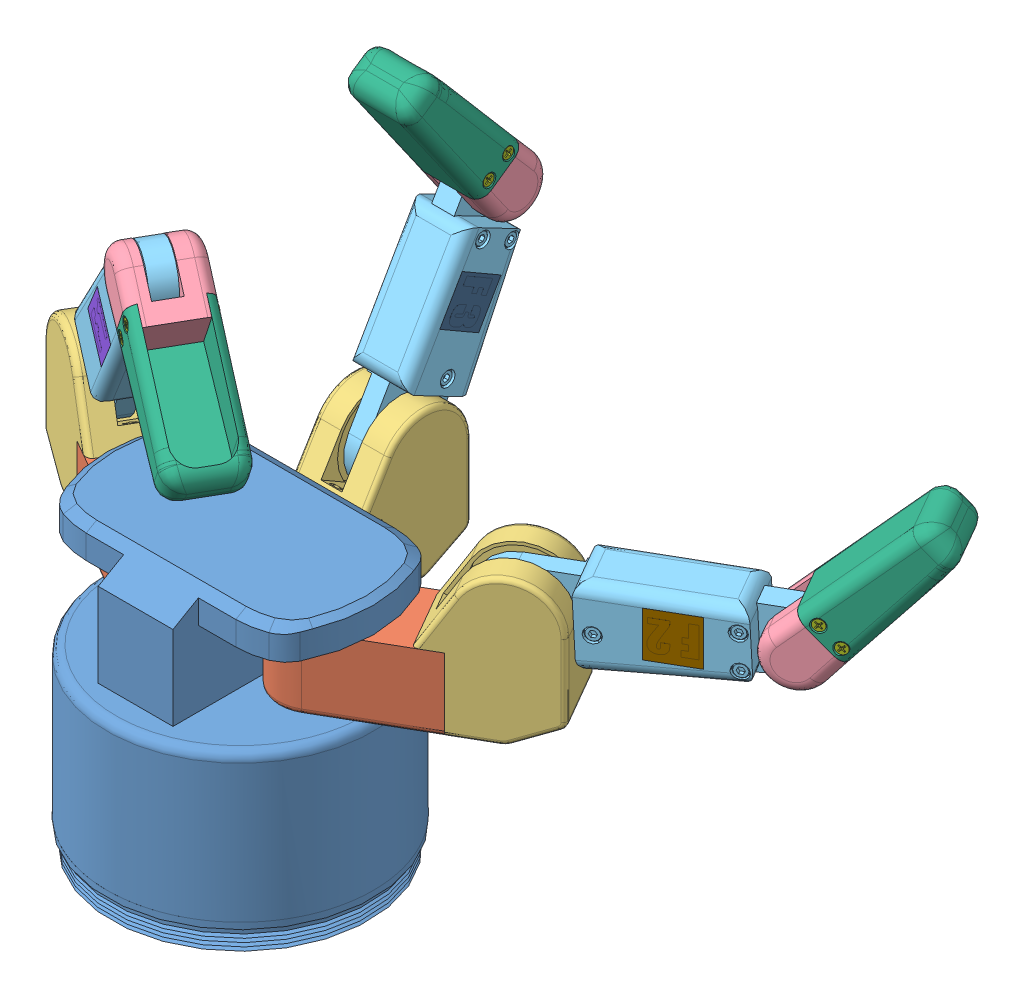
SolidWorks assembly B2579, configuration Default. Lengths in mm.
Overall size (264.08 206.15 142.32).
52 component instances, 10 part files, 12 mates.
Components (placement in the parent):
- B2580-1: B2580 [Default] at (0 -38 0) size (122.92 94.5 88.91)
  - B2581-1: B2581 [Default] at origin size (89 94.5 88.91)
  - B2582-1: B2582 [Default] at (-25 3.2 0) x (-0.5 0 0.866025) z (-0.866025 0 -0.5) size (24.6 24.6 47.3)
  - B2582-2: B2582 [Default] at (25 3.2 0) x (-0.5 0 -0.866025) z (0.866025 0 -0.5) size (24.6 24.6 47.3)
- B2587-1: B2587 [F1] at (-68.3013 -1.1 -25) x (0.5 0 -0.866025) z (0.866025 0 0.5) size (24.6 104.22 112.16)
  - B2583-1: B2583 [Default] at origin size (24.6 48.5 38)
  - B2584-1: B2584 [Default] at (0 55.5766 42.5587) x (1 0 0) z (0 -0.524977 0.851117) size (23 19 25.5)
  - B2585-1: B2585 [Default] x (1 0 0) z (0 0.793951 0.607982) size (19.77 26.65 92)
  - B2586-1: B2586 [Default] at (0.1 18.0923 85.234) x (1 0 0) z (0 -0.524977 0.851117) size (23.31 17.9 46)
    - B0926-1: B0926 [Default] at (0 0 -46) x (-1 0 0) z (0 1 0) size (23.31 46 17.9)
    - B1090-1: B1090 [M2-.4x6] at (10.3 13.5 -43) x (-1 0 0) z (0 0 1) size (6 3.6 3.6)
    - B1090-2: B1090 [M2-.4x6] at (10.3 5.5 -43) x (-1 0 0) z (0 -1 0) size (6 3.6 3.6)
    - B1090-3: B1090 [M2-.4x6] at (-10.3 5.5 -43) size (6 3.6 3.6)
    - B1090-4: B1090 [M2-.4x6] at (-10.3 13.5 -43) x (1 0 0) z (0 -1 0) size (6 3.6 3.6)
  - B0990-1: B0990 [Default] at (9.85 30.4111 25.5623) x (0 -0.819152 -0.573576) z (1 0 0) size (15 15 0.02)
  - B0990-2: B0990 [Default] at (-9.75 30.9368 25.9304) x (0 0.819152 0.573576) z (-1 0 0) size (15 15 0.02)
  - B0991-1: B0991 [Default] at (-9.75 3.4963 -40.215) x (0 0 -1) z (-1 0 0) (suppressed, hidden)
  - B0991-2: B0991 [Default] at (9.85 3.4963 -40.215) x (0 0 1) z (1 0 0) (suppressed, hidden)
  - B0992-1: B0992 [Default] at (-9.75 36.5754 -17.0796) x (0 0.866025 -0.5) z (-1 0 0) (suppressed, hidden)
  - B0992-2: B0992 [Default] at (9.85 36.5754 -17.0796) x (0 -0.866025 0.5) z (1 0 0) (suppressed, hidden)
- B2587-2: B2587 [F2] at (68.3013 -1.1 -25) x (0.5 0 0.866025) z (-0.866025 0 0.5) size (24.6 82.8 138.47)
  - B2583-1: B2583 [Default] at origin size (24.6 48.5 38)
  - B2584-1: B2584 [Default] at (0 2.9847 -69.9363) x (1 0 0) z (0 0.707107 -0.707107) size (23 19 25.5)
  - B2585-1: B2585 [Default] x (1 0 0) z (0 0.042638 -0.999091) size (19.77 26.65 92)
  - B2586-1: B2586 [Default] at (0.1 49.3001 -102.8168) x (1 0 0) z (0 0.707107 -0.707107) size (23.31 17.9 46)
    - B0926-1: B0926 [Default] at (0 0 -46) x (-1 0 0) z (0 1 0) size (23.31 46 17.9)
    - B1090-1: B1090 [M2-.4x6] at (10.3 13.5 -43) x (-1 0 0) z (0 0 1) size (6 3.6 3.6)
    - B1090-2: B1090 [M2-.4x6] at (10.3 5.5 -43) x (-1 0 0) z (0 -1 0) size (6 3.6 3.6)
    - B1090-3: B1090 [M2-.4x6] at (-10.3 5.5 -43) size (6 3.6 3.6)
    - B1090-4: B1090 [M2-.4x6] at (-10.3 13.5 -43) x (1 0 0) z (0 -1 0) size (6 3.6 3.6)
  - B0990-1: B0990 [Default] at (9.85 30.4111 25.5623) x (0 -0.819152 -0.573576) z (1 0 0) size (15 15 0.02) (suppressed, hidden)
  - B0990-2: B0990 [Default] at (-9.75 30.9368 25.9304) x (0 0.819152 0.573576) z (-1 0 0) size (15 15 0.02) (suppressed, hidden)
  - B0991-1: B0991 [Default] at (-9.75 3.4963 -40.215) x (0 0 -1) z (-1 0 0)
  - B0991-2: B0991 [Default] at (9.85 3.4963 -40.215) x (0 0 1) z (1 0 0)
  - B0992-1: B0992 [Default] at (-9.75 36.5754 -17.0796) x (0 0.866025 -0.5) z (-1 0 0) (suppressed, hidden)
  - B0992-2: B0992 [Default] at (9.85 36.5754 -17.0796) x (0 -0.866025 0.5) z (1 0 0) (suppressed, hidden)
- B2587-3: B2587 [F3] at (0 -1.1 -50) size (24.6 146.25 70.86)
  - B2583-1: B2583 [Default] at origin size (24.6 48.5 38)
  - B2584-1: B2584 [Default] at (0 62.059 -32.3834) x (1 0 0) z (0 0.819152 0.573576) size (23 19 25.5)
  - B2585-1: B2585 [Default] x (1 0 0) z (0 0.886557 -0.46262) size (19.77 26.65 92)
  - B2586-1: B2586 [Default] at (0.1 102.4825 7.5188) x (1 0 0) z (0 0.819152 0.573576) size (23.31 17.9 46)
    - B0926-1: B0926 [Default] at (0 0 -46) x (-1 0 0) z (0 1 0) size (23.31 46 17.9)
    - B1090-1: B1090 [M2-.4x6] at (10.3 13.5 -43) x (-1 0 0) z (0 0 1) size (6 3.6 3.6)
    - B1090-2: B1090 [M2-.4x6] at (10.3 5.5 -43) x (-1 0 0) z (0 -1 0) size (6 3.6 3.6)
    - B1090-3: B1090 [M2-.4x6] at (-10.3 5.5 -43) size (6 3.6 3.6)
    - B1090-4: B1090 [M2-.4x6] at (-10.3 13.5 -43) x (1 0 0) z (0 -1 0) size (6 3.6 3.6)
  - B0990-1: B0990 [Default] at (9.85 30.4111 25.5623) x (0 -0.819152 -0.573576) z (1 0 0) size (15 15 0.02) (suppressed, hidden)
  - B0990-2: B0990 [Default] at (-9.75 30.9368 25.9304) x (0 0.819152 0.573576) z (-1 0 0) size (15 15 0.02) (suppressed, hidden)
  - B0991-1: B0991 [Default] at (-9.75 3.4963 -40.215) x (0 0 -1) z (-1 0 0) (suppressed, hidden)
  - B0991-2: B0991 [Default] at (9.85 3.4963 -40.215) x (0 0 1) z (1 0 0) (suppressed, hidden)
  - B0992-1: B0992 [Default] at (-9.75 36.5754 -17.0796) x (0 0.866025 -0.5) z (-1 0 0)
  - B0992-2: B0992 [Default] at (9.85 36.5754 -17.0796) x (0 -0.866025 0.5) z (1 0 0)
Mates (geometry in assembly coordinates):
- J21: limit planar angle = 3.141593 rad: plane of B2587-1/B2583-1 through (-62.1513 -1.1 -35.6521) normal (0.5 0 -0.866025); plane of B2587-3/B2583-1 through (-12.3 -1.1 -50) normal (-1 0 0)
- J22: limit planar angle = 3.141593 rad: plane of ?; plane of ?
- Coincident1: coincident anti-aligned: plane of B2580-1/B2582-1 through (-49.1609 -34.8 -28.1521) normal (-0.866025 0 -0.5); plane of B2587-1/B2583-1 through (-61.4609 -10.2 -6.8479) normal (0.866025 0 0.5)
- Coincident2: coincident anti-aligned: plane of B2580-1/B2582-1 through (-61.4609 -10.2 -6.8479) normal (0 1 0); plane of B2587-1/B2583-1 through (-54.5327 -10.2 -2.8479) normal (0 -1 0)
- Coincident3: coincident aligned: plane of B2580-1/B2582-1 through (-61.4609 -10.2 -6.8479) normal (-0.5 0 0.866025); plane of B2587-1/B2583-1 through (-74.4513 -1.1 -14.3479) normal (-0.5 0 0.866025)
- Coincident4: coincident anti-aligned: plane of B2580-1/B2582-2 through (49.1609 -10.2 -28.1521) normal (0 1 0); plane of B2587-2/B2583-1 through (42.2327 -10.2 -24.1521) normal (0 -1 0)
- Coincident5: coincident anti-aligned: plane of B2580-1/B2582-2 through (61.4609 -34.8 -6.8479) normal (0.866025 0 -0.5); plane of B2587-2/B2583-1 through (49.1609 -10.2 -28.1521) normal (-0.866025 0 0.5)
- Coincident6: coincident aligned: plane of B2580-1/B2582-2 through (61.4609 -34.8 -6.8479) normal (0.5 0 0.866025); plane of B2587-2/B2583-1 through (74.4513 -1.1 -14.3479) normal (0.5 0 0.866025)
- Coincident7: coincident anti-aligned: plane of B2580-1/B2581-1 through (12.3 -34.8 -35) normal (0 0 -1); plane of B2587-3/B2583-1 through (-12.3 -10.2 -35) normal (0 0 1)
- Coincident8: coincident anti-aligned: plane of B2580-1/B2581-1 through (-12.3 -10.2 -35) normal (0 1 0); plane of B2587-3/B2583-1 through (-12.3 -10.2 -27) normal (0 -1 0)
- Coincident9: coincident aligned: plane of B2580-1/B2581-1 through (-12.3 -10.2 -35) normal (-1 0 0); plane of B2587-3/B2583-1 through (-12.3 -1.1 -50) normal (-1 0 0)
- Concentric1: concentric aligned: cylinder of B2580-1/B2581-1 through (0 -38 0) axis (0 -1 0) radius 44.45; line of assembly
